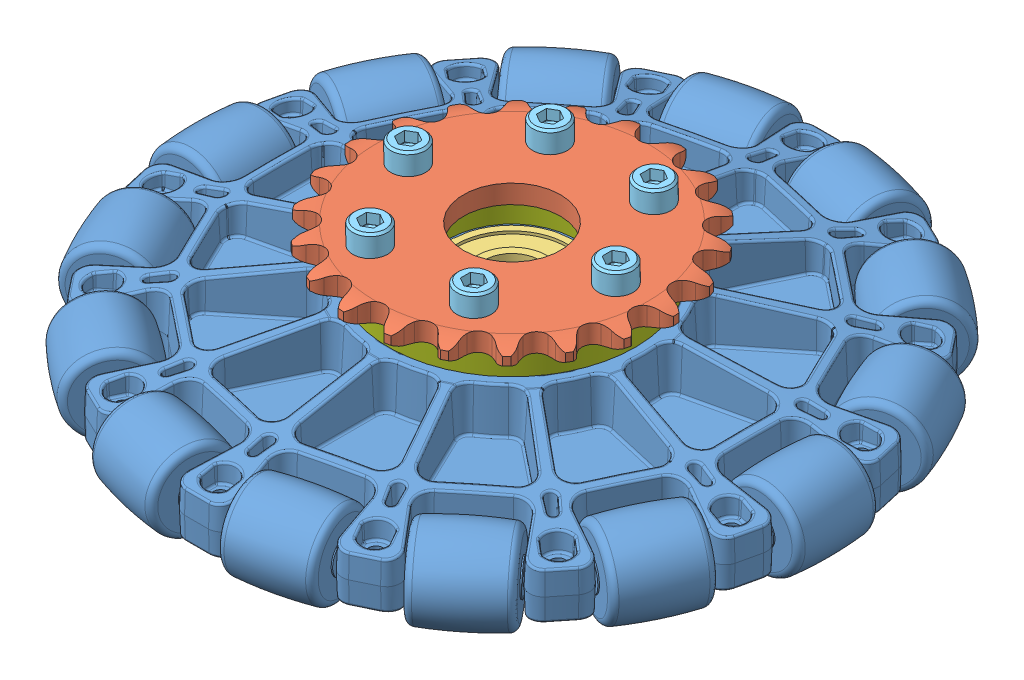
SolidWorks assembly omni_wheel_assm, configuration Default. Lengths in mm.
Overall size (152.04 49.28 152.39).
17 component instances, 7 part files, 34 mates.
Components (placement in the parent):
- 6inch_omni-1: 6inch_omni [Default] at (-5.8198 16.297 -20.6554) size (152.04 25.4 152.39)
- sprocket_spacer_22t-1: sprocket_spacer_22t [Default] at (-5.8198 50.1854 -20.6554) x (0 1 0) z (-0.866025 0 -0.5) size (5.07 71.91 71.96)
- plain 0500 bearing-1: plain 0500 bearing [Default] at (-5.8198 37.7283 -20.6554) x (1 0 0) z (0 1 0) size (28.57 28.57 7.94)
- flanged 0500 bearing-1: flanged 0500 bearing [Default] at (-5.8198 18.6783 -20.6554) x (0.923728 0 -0.383049) z (0 -1 0) size (31.75 31.75 7.94)
- Socket Head Cap Screw_AI-1: Socket Head Cap Screw_AI [HX-SHCS 0.19-32x1.75x1.75-C] at (17.9927 57.1498 -20.6554) x (0 -1 0) z (1 0 0) size (49.28 7.94 7.94)
- Socket Head Cap Screw_AI-2: Socket Head Cap Screw_AI [HX-SHCS 0.19-32x1.75x1.75-C] at (-29.6323 57.1498 -20.6554) x (0 -1 0) z (1 0 0) size (49.28 7.94 7.94)
- Socket Head Cap Screw_AI-3: Socket Head Cap Screw_AI [HX-SHCS 0.19-32x1.75x1.75-C] at (-17.726 57.1498 -0.0332) x (0 -1 0) z (1 0 0) size (49.28 7.94 7.94)
- Socket Head Cap Screw_AI-4: Socket Head Cap Screw_AI [HX-SHCS 0.19-32x1.75x1.75-C] at (6.0865 57.1498 -0.0332) x (0 -1 0) z (1 0 0) size (49.28 7.94 7.94)
- Socket Head Cap Screw_AI-5: Socket Head Cap Screw_AI [HX-SHCS 0.19-32x1.75x1.75-C] at (6.0865 57.1498 -41.2777) x (0 -1 0) z (1 0 0) size (49.28 7.94 7.94)
- Socket Head Cap Screw_AI-6: Socket Head Cap Screw_AI [HX-SHCS 0.19-32x1.75x1.75-C] at (-17.726 57.1498 -41.2777) x (0 -1 0) z (1 0 0) size (49.28 7.94 7.94)
- Machine Screw Nut Hex_AI-1: Machine Screw Nut Hex_AI [MSHXNUT 0.190-32-S-N] at (-17.726 16.297 -41.2777) x (1 0 0) z (0 1 0) size (9.53 11 3.3)
- Machine Screw Nut Hex_AI-2: Machine Screw Nut Hex_AI [MSHXNUT 0.190-32-S-N] at (6.0865 16.297 -41.2777) x (1 0 0) z (0 1 0) size (9.53 11 3.3)
- Machine Screw Nut Hex_AI-3: Machine Screw Nut Hex_AI [MSHXNUT 0.190-32-S-N] at (17.9927 16.297 -20.6554) x (1 0 0) z (0 1 0) size (9.53 11 3.3)
- Machine Screw Nut Hex_AI-4: Machine Screw Nut Hex_AI [MSHXNUT 0.190-32-S-N] at (6.0865 12.995 -0.0332) x (0.923728 0 -0.383049) z (0 -1 0) size (9.53 11 3.3)
- Machine Screw Nut Hex_AI-5: Machine Screw Nut Hex_AI [MSHXNUT 0.190-32-S-N] at (-29.6323 16.297 -20.6554) x (1 0 0) z (0 1 0) size (9.53 11 3.3)
- Machine Screw Nut Hex_AI-6: Machine Screw Nut Hex_AI [MSHXNUT 0.190-32-S-N] at (-17.726 16.297 -0.0332) x (1 0 0) z (0 1 0) size (9.53 11 3.3)
- sprocket_spacer-1: sprocket_spacer [Default] at (-5.8198 44.872 -20.6554) x (0.866025 0 0.5) z (0 -1 0) size (57.15 57.15 6.35)
Mates (geometry in assembly coordinates):
- Concentric7: concentric aligned: cylinder of 6inch_omni-1 through (-17.726 67.097 -41.2777) axis (0 1 0) radius 2.5908; circle of sprocket_spacer_22t-1
- Concentric8: concentric aligned: cylinder of 6inch_omni-1 through (-29.6323 67.097 -20.6554) axis (0 1 0) radius 2.5908; circle of sprocket_spacer_22t-1
- Concentric9: concentric anti-aligned: cylinder of 6inch_omni-1 through (-5.8198 34.077 -20.6554) axis (0 -1 0) radius 14.2812; cylinder of plain 0500 bearing-1 through (-5.8198 37.7283 -20.6554) axis (0 1 0) radius 14.2875
- Coincident8: coincident aligned: plane of 6inch_omni-1 through (-64.3668 41.697 -27.1324) normal (0 1 0); plane of plain 0500 bearing-1 through (-5.0809 41.697 -20.6554) normal (0 1 0)
- Concentric10: concentric anti-aligned: cylinder of 6inch_omni-1 through (-5.8198 23.917 -20.6554) axis (0 1 0) radius 14.2812; cylinder of flanged 0500 bearing-1 through (-5.8198 18.6783 -20.6554) axis (0 -1 0) radius 14.2875
- Coincident9: coincident anti-aligned: plane of 6inch_omni-1 through (-64.3668 16.297 -14.1784) normal (0 -1 0); plane of flanged 0500 bearing-1 through (-4.4867 16.297 -21.2083) normal (0 1 0)
- Concentric11: concentric aligned: circle of sprocket_spacer_22t-1; cylinder of Socket Head Cap Screw_AI-6 through (-17.726 166.0579 -41.2777) axis (0 1 0) radius 2.413
- Coincident10: coincident anti-aligned: plane of sprocket_spacer_22t-1 through (1.985 129.4819 -34.1736) normal (0 1 0); plane of Socket Head Cap Screw_AI-6 through (-17.726 129.4819 -45.2464) normal (0 -1 0)
- Concentric12: concentric aligned: circle of sprocket_spacer_22t-1; cylinder of Socket Head Cap Screw_AI-2 through (-29.6323 166.0579 -20.6554) axis (0 1 0) radius 2.413
- Coincident11: coincident anti-aligned: plane of sprocket_spacer_22t-1 through (1.985 129.4819 -34.1736) normal (0 1 0); plane of Socket Head Cap Screw_AI-2 through (-29.6323 129.4819 -24.6242) normal (0 -1 0)
- Concentric13: concentric aligned: circle of sprocket_spacer_22t-1; cylinder of Socket Head Cap Screw_AI-3 through (-17.726 166.0579 -0.0332) axis (0 1 0) radius 2.413
- Coincident12: coincident anti-aligned: plane of sprocket_spacer_22t-1 through (1.985 129.4819 -34.1736) normal (0 1 0); plane of Socket Head Cap Screw_AI-3 through (-17.726 129.4819 -4.002) normal (0 -1 0)
- Concentric14: concentric anti-aligned: cylinder of sprocket_spacer_22t-1 through (6.0865 125.2051 -0.0332) axis (0 -1 0) radius 2.6162; cylinder of Socket Head Cap Screw_AI-4 through (6.0865 166.0579 -0.0332) axis (0 1 0) radius 2.413
- Coincident13: coincident anti-aligned: plane of sprocket_spacer_22t-1 through (1.985 129.4819 -34.1736) normal (0 1 0); plane of Socket Head Cap Screw_AI-4 through (6.0865 129.4819 -4.002) normal (0 -1 0)
- Concentric15: concentric aligned: circle of sprocket_spacer_22t-1; cylinder of Socket Head Cap Screw_AI-1 through (17.9927 166.0579 -20.6554) axis (0 1 0) radius 2.413
- Concentric16: concentric aligned: circle of sprocket_spacer_22t-1; cylinder of Socket Head Cap Screw_AI-5 through (6.0865 166.0579 -41.2777) axis (0 1 0) radius 2.413
- Coincident14: coincident anti-aligned: plane of sprocket_spacer_22t-1 through (1.985 129.4819 -34.1736) normal (0 1 0); plane of Socket Head Cap Screw_AI-1 through (17.9927 129.4819 -24.6242) normal (0 -1 0)
- Coincident15: coincident anti-aligned: plane of sprocket_spacer_22t-1 through (1.985 129.4819 -34.1736) normal (0 1 0); plane of Socket Head Cap Screw_AI-5 through (6.0865 129.4819 -45.2464) normal (0 -1 0)
- Coincident16: coincident aligned: cylinder of Socket Head Cap Screw_AI-6 through (-17.726 88.8998 -41.2777) axis (0 1 0) radius 2.413; circle of Machine Screw Nut Hex_AI-1
- Coincident17: coincident anti-aligned: plane of 6inch_omni-1 through (-64.3668 16.297 -14.1784) normal (0 -1 0); plane of Machine Screw Nut Hex_AI-1 through (-17.726 16.297 -46.7769) normal (0 1 0)
- Coincident18: coincident aligned: cylinder of Socket Head Cap Screw_AI-5 through (6.0865 88.8998 -41.2777) axis (0 1 0) radius 2.413; circle of Machine Screw Nut Hex_AI-2
- Coincident19: coincident aligned: cylinder of Socket Head Cap Screw_AI-1 through (17.9927 88.8998 -20.6554) axis (0 1 0) radius 2.413; circle of Machine Screw Nut Hex_AI-3
- Coincident20: coincident anti-aligned: plane of 6inch_omni-1 through (-64.3668 16.297 -14.1784) normal (0 -1 0); plane of Machine Screw Nut Hex_AI-3 through (17.9927 16.297 -26.1547) normal (0 1 0)
- Coincident21: coincident anti-aligned: plane of 6inch_omni-1 through (-64.3668 16.297 -14.1784) normal (0 -1 0); plane of Machine Screw Nut Hex_AI-2 through (6.0865 16.297 -46.7769) normal (0 1 0)
- Concentric17: concentric anti-aligned: circle of Socket Head Cap Screw_AI-4; circle of Machine Screw Nut Hex_AI-4
- Concentric18: concentric aligned: circle of Socket Head Cap Screw_AI-3; circle of Machine Screw Nut Hex_AI-6
- Concentric19: concentric aligned: circle of Socket Head Cap Screw_AI-2; circle of Machine Screw Nut Hex_AI-5
- Coincident24: coincident anti-aligned: plane of 6inch_omni-1 through (-64.3668 16.297 -14.1784) normal (0 -1 0); plane of Machine Screw Nut Hex_AI-5 through (-29.6323 16.297 -26.1547) normal (0 1 0)
- Coincident25: coincident anti-aligned: plane of 6inch_omni-1 through (-64.3668 16.297 -14.1784) normal (0 -1 0); plane of Machine Screw Nut Hex_AI-6 through (-17.726 16.297 -5.5325) normal (0 1 0)
- Coincident26: coincident anti-aligned: plane of 6inch_omni-1 through (-64.3668 16.297 -14.1784) normal (0 -1 0); plane of Machine Screw Nut Hex_AI-4 through (8.193 16.297 5.0466) normal (0 1 0)
- Concentric20: concentric aligned: circle of 6inch_omni-1; circle of sprocket_spacer-1
- Concentric21: concentric aligned: circle of 6inch_omni-1; circle of sprocket_spacer-1
- Coincident27: coincident anti-aligned: plane of 6inch_omni-1 through (-64.3668 41.697 -27.1324) normal (0 1 0); plane of sprocket_spacer-1 through (-5.8198 41.697 -20.6554) normal (0 -1 0)
- Coincident28: coincident anti-aligned: plane of sprocket_spacer_22t-1 through (1.985 48.047 -34.1736) normal (0 -1 0); plane of sprocket_spacer-1 through (18.9269 48.047 -6.3679) normal (0 1 0)
